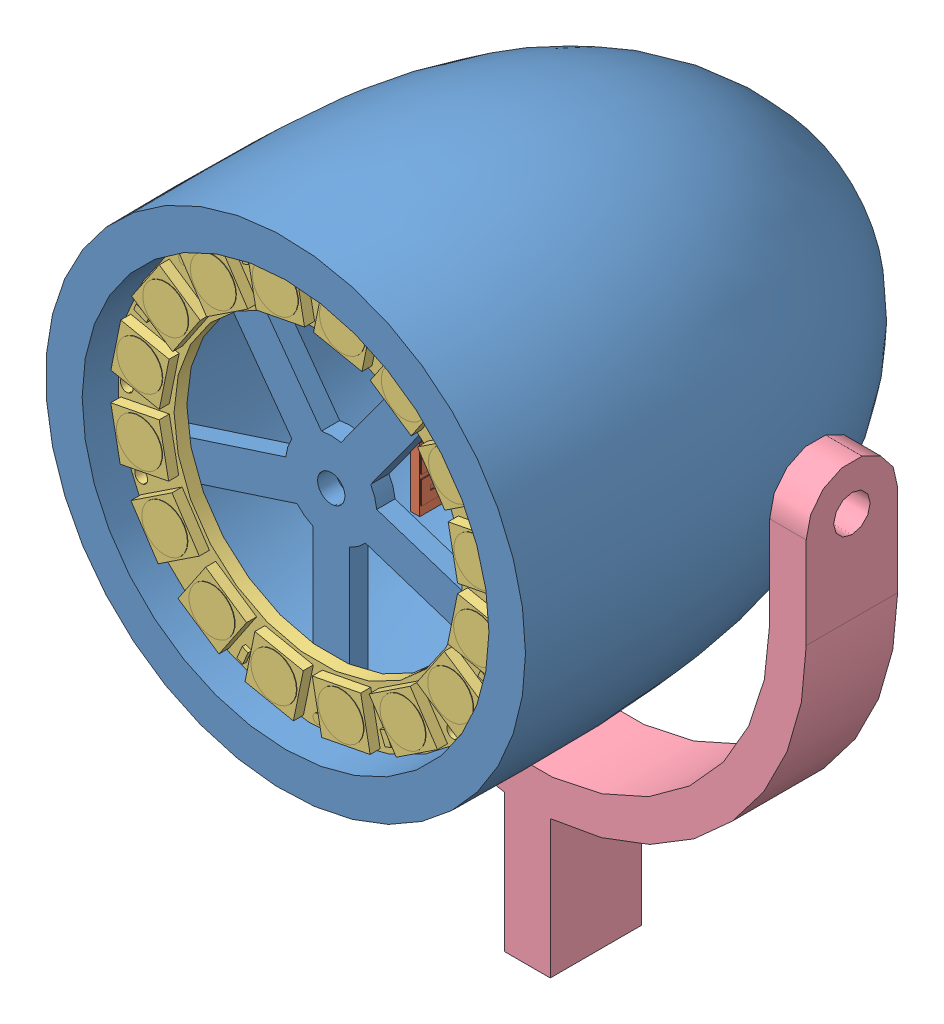
SolidWorks assembly assembly, configuration Default. Lengths in mm.
Overall size (61 81.48 54).
4 component instances, 4 part files, 2 mates.
Components (placement in the parent):
- shell-2: shell [Default] at (4.7667 35.8768 21.3418) x (1 0 0) z (0 0 -1) size (52.66 52.66 54)
- ESP 01-1: ESP 01 [Default] at (6.1172 30.6968 34.017) x (0 0 1) z (0 1 0) size (25 10.86 15)
- NeoPixelRing16-1: NeoPixelRing16 [Default] at (4.7667 35.8768 66.6418) size (44 44 2.55)
- movingArm-1: movingArm [Default] at (5.4839 26.2252 35.6026) size (61 60.5 10)
Mates (geometry in assembly coordinates):
- Coincident1: coincident anti-aligned: plane of shell-2 through (4.7667 35.8768 66.3418) normal (0 0 1); plane of NeoPixelRing16-1 through (4.8259 36.1607 66.3418) normal (0 0 -1)
- Concentric1: concentric aligned: circle of shell-2; cylinder of NeoPixelRing16-1 through (4.7667 35.8768 66.3418) axis (0 0 -1) radius 22
